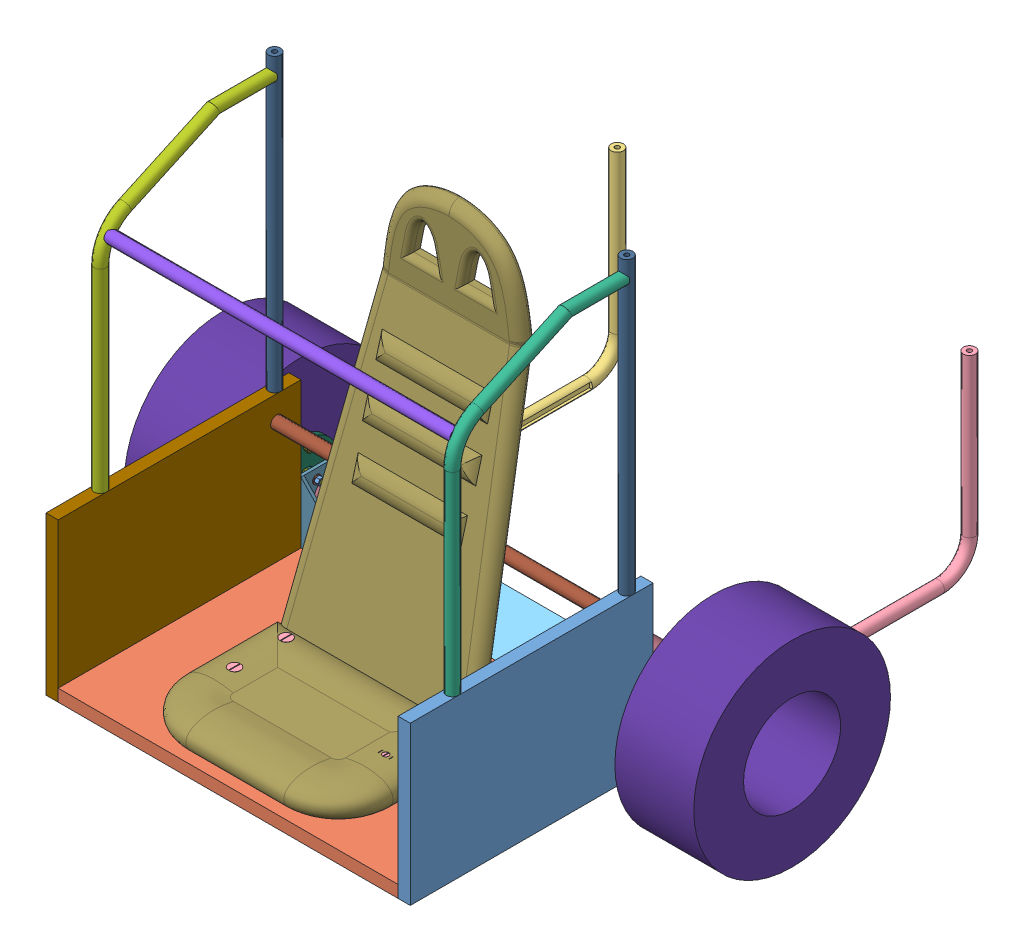
SolidWorks assembly MC (1), configuration Default. Lengths in mm.
Overall size (1191.26 1083.62 1291.85).
109 component instances, 22 part files, 141 mates.
Components (placement in the parent):
- SPL-1: SPL [Default] at (646.5449 178.7927 -996.551) size (25.4 330.2 508)
- BP-1: BP [Default] at (111.0665 -124.6065 -917.4807) size (711.2 25.4 508)
- BBR-2: BBR [Default] at (-77.3551 -47.0728 -1647.3326) x (-1 0 0) z (0 -1 0) size (25.4 687.13 407.73)
- BBL-1: BBL [Default] at (659.2449 -47.0728 -1647.3326) x (-1 0 0) z (0 -1 0) size (25.4 687.13 407.73)
- BC-1: BC [Default] at (357.2961 -116.9228 -1190.1326) x (-1 0 0) z (0 0 -1) size (723.9 12.7 152.4)
- FTL-1: FTL [Default] at (659.245 611.9935 -719.4116) x (0 -0.899323 -0.437285) z (-1 0 -0.000001) size (433.75 589.6 27.41)
- FTR-1: FTR [Default] at (-77.355 611.9935 -719.4116) x (0 -0.899323 -0.437285) z (-1 0 -0.000001) size (433.75 589.6 27.38)
- TC-1: TC [Default] at (652.8949 660.2535 -644.2461) x (0 -0.542655 -0.839955) z (-1 0 -0.000001) size (25.4 25.4 723.9)
- SPR-1: SPR [Default] at (-90.0551 178.7927 -996.551) size (25.4 330.2 508)
- BT-1: BT [Default] at (-77.3551 205.5935 -995.2506) x (0.000001 0 -1) z (1 0 0.000001) size (25.4 609.6 25.4)
- BT-2: BT [Default] at (659.2449 205.5935 -995.2506) x (0.000001 0 -1) z (1 0 0.000001) size (25.4 609.6 25.4)
- FB-1: FB [Default] at (-71.0051 154.7935 -986.9326) x (1 0 0) z (0 0.990518 0.137381) size (723.9 25.4 25.4)
- seat-1: seat [Default] at (291.4237 -99.2065 -836.1249) size (437.03 835.23 478.09)
- EA1-1: EA1 [Default] at (125.7912 -160.5315 -1174.1403) x (0 0 1) z (-1 0 0) size (411.48 411.48 1349.16)
  - EB1-1: EB1 [Default] at (60.2077 126.1588 196.7963) size (101.6 101.6 238.25)
  - EP1-1: EP1 [Default] at (60.2077 56.3088 69.7963) x (0 0 1) z (-1 0 0) size (254 133.35 152.4)
  - EA2-1: EA2 [Default] at (45.9187 58.6487 138.5565) size (411.48 411.48 213.36)
    - EP2-1: EP2 [Default] at (14.289 67.5101 114.1198) size (127 127 48.26)
    - hex bolt_ai-1: hex bolt_ai [HBOLT 0.4375-20x1.375x1.125-N] at (-36.511 67.5101 106.0934) x (0 0 1) z (-0.866025 -0.5 0) size (42.95 18.33 15.88)
    - hex bolt_ai-2: hex bolt_ai [HBOLT 0.4375-20x1.375x1.125-N] at (14.289 118.3101 106.0934) x (0 0 1) z (0 -1 0) size (42.95 18.33 15.88)
    - hex bolt_ai-3: hex bolt_ai [HBOLT 0.4375-20x1.375x1.125-N] at (14.289 16.7101 106.0934) x (0 0 1) z (-0.866025 0.5 0) size (42.95 18.33 15.88)
    - hex bolt_ai-4: hex bolt_ai [HBOLT 0.4375-20x1.375x1.125-N] at (65.089 67.5101 106.0934) x (0 0 1) z (-0.866025 0.5 0) size (42.95 18.33 15.88)
    - EB2-1: EB2 [Default] at (14.289 67.5101 129.9948) x (-1 0 0) z (0 0 -1) size (411.48 411.48 165.1)
    - flat washer type a wide_ai-1: flat washer type a wide_ai [Preferred Wide FW 0.4375] at (-36.511 67.5101 132.103) x (0 0 1) z (-0.923728 -0.383049 0) size (2.11 31.75 31.75)
    - flat washer type a wide_ai-2: flat washer type a wide_ai [Preferred Wide FW 0.4375] at (14.289 118.3101 132.103) x (0 0 1) z (1 0 0) size (2.11 31.75 31.75)
    - flat washer type a wide_ai-3: flat washer type a wide_ai [Preferred Wide FW 0.4375] at (14.289 16.7101 132.103) x (0 0 1) z (1 0 0) size (2.11 31.75 31.75)
    - flat washer type a wide_ai-4: flat washer type a wide_ai [Preferred Wide FW 0.4375] at (65.089 67.5101 132.103) x (0 0 1) z (1 0 0) size (2.11 31.75 31.75)
    - hex thick nut_ai-1: hex thick nut_ai [HTNUT 0.4375-14-D-N] at (14.289 16.7101 143.8632) x (0.055202 -0.998475 0) z (0 0 1) size (17.48 20.18 11.76)
    - hex thick nut_ai-2: hex thick nut_ai [HTNUT 0.4375-14-D-N] at (-36.511 67.5101 143.8632) x (0.547044 -0.837104 0) z (0 0 1) size (17.48 20.18 11.76)
    - hex thick nut_ai-3: hex thick nut_ai [HTNUT 0.4375-14-D-N] at (65.089 67.5101 143.8632) x (-0.982324 -0.18719 0) z (0 0 1) size (17.48 20.18 11.76)
    - hex thick nut_ai-4: hex thick nut_ai [HTNUT 0.4375-14-D-N] at (14.289 118.3101 143.8632) x (0.055202 -0.998475 0) z (0 0 1) size (17.48 20.18 11.76)
  - hex bolt_ai-8: hex bolt_ai [HBOLT 0.3125-18x1.375x0.875-N] at (17.0277 169.3388 215.4653) x (0 0 -1) z (0 1 0) size (40.89 14.66 12.7)
  - hex bolt_ai-9: hex bolt_ai [HBOLT 0.3125-18x1.375x0.875-N] at (103.3877 169.3388 215.4653) x (0 0 -1) z (0.866025 -0.5 0) size (40.89 14.66 12.7)
  - hex bolt_ai-10: hex bolt_ai [HBOLT 0.3125-18x1.375x0.875-N] at (103.3877 82.9788 215.4653) x (0 0 -1) z (0.866025 0.5 0) size (40.89 14.66 12.7)
  - hex bolt_ai-11: hex bolt_ai [HBOLT 0.3125-18x1.375x0.875-N] at (17.0277 82.9788 215.4653) x (0 0 -1) z (-0.866025 -0.5 0) size (40.89 14.66 12.7)
  - flat washer type a narrow_ai-1: flat washer type a narrow_ai [Preferred Narrow FW 0.3125] at (17.0277 169.3388 190.4463) x (0 0 1) z (-1 0 0) size (1.65 17.48 17.48)
  - flat washer type a narrow_ai-2: flat washer type a narrow_ai [Preferred Narrow FW 0.3125] at (103.3877 82.9788 190.4463) x (0 0 1) z (-1 0 0) size (1.65 17.48 17.48)
  - flat washer type a narrow_ai-3: flat washer type a narrow_ai [Preferred Narrow FW 0.3125] at (17.0277 82.9788 188.7953) x (0 0 -1) z (1 0 0) size (1.65 17.48 17.48)
  - flat washer type a narrow_ai-4: flat washer type a narrow_ai [Preferred Narrow FW 0.3125] at (103.3877 169.3388 188.7953) x (0 0 -1) z (0.923728 0.383049 0) size (1.65 17.48 17.48)
  - hex thick nut_ai-1: hex thick nut_ai [HTNUT 0.3125-18-D-N] at (103.3877 169.3388 188.7953) x (0.866025 0.5 0) z (0 0 1) size (12.7 14.66 8.53)
  - hex thick nut_ai-2: hex thick nut_ai [HTNUT 0.3125-18-D-N] at (17.0277 82.9788 180.2609) x (-0.866025 0.5 0) z (0 0 -1) size (12.7 14.66 8.53)
  - hex thick nut_ai-3: hex thick nut_ai [HTNUT 0.3125-18-D-N] at (103.3877 82.9788 181.9119) x (-0.866025 -0.5 0) z (0 0 -1) size (12.7 14.66 8.53)
  - hex thick nut_ai-4: hex thick nut_ai [HTNUT 0.3125-18-D-N] at (17.0277 169.3388 180.2609) x (-0.866025 -0.5 0) z (0 0 -1) size (12.7 14.66 8.53)
- EA1-2: EA1 [Default] at (456.0986 -160.5315 -1053.7249) x (0 0 -1) z (1 0 0) size (411.48 411.48 1349.16)
  - EB1-1: EB1 [Default] at (60.2077 126.1588 196.7963) size (101.6 101.6 238.25)
  - EP1-1: EP1 [Default] at (60.2077 56.3088 69.7963) x (0 0 1) z (-1 0 0) size (254 133.35 152.4)
  - EA2-1: EA2 [Default] at (45.9187 58.6487 138.5565) size (411.48 411.48 213.36)
    - EP2-1: EP2 [Default] at (14.289 67.5101 114.1198) size (127 127 48.26)
    - hex bolt_ai-1: hex bolt_ai [HBOLT 0.4375-20x1.375x1.125-N] at (-36.511 67.5101 106.0934) x (0 0 1) z (-0.866025 -0.5 0) size (42.95 18.33 15.88)
    - hex bolt_ai-2: hex bolt_ai [HBOLT 0.4375-20x1.375x1.125-N] at (14.289 118.3101 106.0934) x (0 0 1) z (0 -1 0) size (42.95 18.33 15.88)
    - hex bolt_ai-3: hex bolt_ai [HBOLT 0.4375-20x1.375x1.125-N] at (14.289 16.7101 106.0934) x (0 0 1) z (-0.866025 0.5 0) size (42.95 18.33 15.88)
    - hex bolt_ai-4: hex bolt_ai [HBOLT 0.4375-20x1.375x1.125-N] at (65.089 67.5101 106.0934) x (0 0 1) z (-0.866025 0.5 0) size (42.95 18.33 15.88)
    - EB2-1: EB2 [Default] at (14.289 67.5101 129.9948) x (-1 0 0) z (0 0 -1) size (411.48 411.48 165.1)
    - flat washer type a wide_ai-1: flat washer type a wide_ai [Preferred Wide FW 0.4375] at (-36.511 67.5101 132.103) x (0 0 1) z (-0.923728 -0.383049 0) size (2.11 31.75 31.75)
    - flat washer type a wide_ai-2: flat washer type a wide_ai [Preferred Wide FW 0.4375] at (14.289 118.3101 132.103) x (0 0 1) z (1 0 0) size (2.11 31.75 31.75)
    - flat washer type a wide_ai-3: flat washer type a wide_ai [Preferred Wide FW 0.4375] at (14.289 16.7101 132.103) x (0 0 1) z (1 0 0) size (2.11 31.75 31.75)
    - flat washer type a wide_ai-4: flat washer type a wide_ai [Preferred Wide FW 0.4375] at (65.089 67.5101 132.103) x (0 0 1) z (1 0 0) size (2.11 31.75 31.75)
    - hex thick nut_ai-1: hex thick nut_ai [HTNUT 0.4375-14-D-N] at (14.289 16.7101 143.8632) x (0.055202 -0.998475 0) z (0 0 1) size (17.48 20.18 11.76)
    - hex thick nut_ai-2: hex thick nut_ai [HTNUT 0.4375-14-D-N] at (-36.511 67.5101 143.8632) x (0.547044 -0.837104 0) z (0 0 1) size (17.48 20.18 11.76)
    - hex thick nut_ai-3: hex thick nut_ai [HTNUT 0.4375-14-D-N] at (65.089 67.5101 143.8632) x (-0.982324 -0.18719 0) z (0 0 1) size (17.48 20.18 11.76)
    - hex thick nut_ai-4: hex thick nut_ai [HTNUT 0.4375-14-D-N] at (14.289 118.3101 143.8632) x (0.055202 -0.998475 0) z (0 0 1) size (17.48 20.18 11.76)
  - hex bolt_ai-8: hex bolt_ai [HBOLT 0.3125-18x1.375x0.875-N] at (17.0277 169.3388 215.4653) x (0 0 -1) z (0 1 0) size (40.89 14.66 12.7)
  - hex bolt_ai-9: hex bolt_ai [HBOLT 0.3125-18x1.375x0.875-N] at (103.3877 169.3388 215.4653) x (0 0 -1) z (0.866025 -0.5 0) size (40.89 14.66 12.7)
  - hex bolt_ai-10: hex bolt_ai [HBOLT 0.3125-18x1.375x0.875-N] at (103.3877 82.9788 215.4653) x (0 0 -1) z (0.866025 0.5 0) size (40.89 14.66 12.7)
  - hex bolt_ai-11: hex bolt_ai [HBOLT 0.3125-18x1.375x0.875-N] at (17.0277 82.9788 215.4653) x (0 0 -1) z (-0.866025 -0.5 0) size (40.89 14.66 12.7)
  - flat washer type a narrow_ai-1: flat washer type a narrow_ai [Preferred Narrow FW 0.3125] at (17.0277 169.3388 190.4463) x (0 0 1) z (-1 0 0) size (1.65 17.48 17.48)
  - flat washer type a narrow_ai-2: flat washer type a narrow_ai [Preferred Narrow FW 0.3125] at (103.3877 82.9788 190.4463) x (0 0 1) z (-1 0 0) size (1.65 17.48 17.48)
  - flat washer type a narrow_ai-3: flat washer type a narrow_ai [Preferred Narrow FW 0.3125] at (17.0277 82.9788 188.7953) x (0 0 -1) z (1 0 0) size (1.65 17.48 17.48)
  - flat washer type a narrow_ai-4: flat washer type a narrow_ai [Preferred Narrow FW 0.3125] at (103.3877 169.3388 188.7953) x (0 0 -1) z (0.923728 0.383049 0) size (1.65 17.48 17.48)
  - hex thick nut_ai-1: hex thick nut_ai [HTNUT 0.3125-18-D-N] at (103.3877 169.3388 188.7953) x (0.866025 0.5 0) z (0 0 1) size (12.7 14.66 8.53)
  - hex thick nut_ai-2: hex thick nut_ai [HTNUT 0.3125-18-D-N] at (17.0277 82.9788 180.2609) x (-0.866025 0.5 0) z (0 0 -1) size (12.7 14.66 8.53)
  - hex thick nut_ai-3: hex thick nut_ai [HTNUT 0.3125-18-D-N] at (103.3877 82.9788 181.9119) x (-0.866025 -0.5 0) z (0 0 -1) size (12.7 14.66 8.53)
  - hex thick nut_ai-4: hex thick nut_ai [HTNUT 0.3125-18-D-N] at (17.0277 169.3388 180.2609) x (-0.866025 -0.5 0) z (0 0 -1) size (12.7 14.66 8.53)
- hex bolt_ai-1: hex bolt_ai [HBOLT 0.5000-13x1.375x1.25-N] at (157.5949 -88.6272 -1164.7326) x (0 -1 0) z (-1 0 0) size (44.17 22 19.05)
- hex bolt_ai-2: hex bolt_ai [HBOLT 0.5000-13x1.375x1.25-N] at (157.5949 -88.6272 -1063.1326) x (0 -1 0) z (0.5 0 -0.866025) size (44.17 22 19.05)
- hex bolt_ai-3: hex bolt_ai [HBOLT 0.5000-13x1.375x1.25-N] at (424.2949 -88.6272 -1063.1326) x (0 -1 0) z (1 0 0) size (44.17 22 19.05)
- hex bolt_ai-4: hex bolt_ai [HBOLT 0.5000-13x1.375x1.25-N] at (602.0949 -88.6272 -1164.7326) x (0 -1 0) z (-0.5 0 -0.866025) size (44.17 22 19.05)
- hex bolt_ai-5: hex bolt_ai [HBOLT 0.5000-13x1.375x1.25-N] at (424.2949 -88.6272 -1164.7326) x (0 -1 0) z (0.5 0 -0.866025) size (44.17 22 19.05)
- hex bolt_ai-6: hex bolt_ai [HBOLT 0.5000-13x1.375x1.25-N] at (602.0949 -88.6272 -1063.1326) x (0 -1 0) z (-0.5 0 0.866025) size (44.17 22 19.05)
- hex bolt_ai-7: hex bolt_ai [HBOLT 0.5000-13x1.375x1.25-N] at (-20.2051 -88.6272 -1164.7326) x (0 -1 0) z (-1 0 0) size (44.17 22 19.05)
- hex bolt_ai-8: hex bolt_ai [HBOLT 0.5000-13x1.375x1.25-N] at (-20.2051 -88.6272 -1063.1326) x (0 -1 0) z (1 0 0) size (44.17 22 19.05)
- flat washer type a wide_ai-1: flat washer type a wide_ai [Preferred Wide FW 0.5] at (157.5949 -119.6914 -1063.1326) x (0 -1 0) z (0.546944 0 -0.837169) size (2.77 34.92 34.92)
- flat washer type a wide_ai-2: flat washer type a wide_ai [Preferred Wide FW 0.5] at (157.5949 -119.6914 -1164.7326) x (0 -1 0) z (0.967366 0 0.253384) size (2.77 34.92 34.92)
- flat washer type a wide_ai-3: flat washer type a wide_ai [Preferred Wide FW 0.5] at (424.2949 -119.6914 -1164.7326) x (0 -1 0) z (-0.558017 0 -0.829829) size (2.77 34.92 34.92)
- flat washer type a wide_ai-4: flat washer type a wide_ai [Preferred Wide FW 0.5] at (-20.2051 -119.6914 -1063.1326) x (0 -1 0) z (0.590888 0 -0.806754) size (2.77 34.92 34.92)
- flat washer type a wide_ai-5: flat washer type a wide_ai [Preferred Wide FW 0.5] at (602.0949 -119.6914 -1063.1326) x (0 -1 0) z (0.610265 0 -0.792197) size (2.77 34.92 34.92)
- flat washer type a wide_ai-6: flat washer type a wide_ai [Preferred Wide FW 0.5] at (424.2949 -119.6914 -1063.1326) x (0 -1 0) z (0.837672 0 -0.546174) size (2.77 34.92 34.92)
- flat washer type a wide_ai-7: flat washer type a wide_ai [Preferred Wide FW 0.5] at (602.0949 -119.6914 -1164.7326) x (0 -1 0) z (0.97172 0 -0.236136) size (2.77 34.92 34.92)
- flat washer type a wide_ai-8: flat washer type a wide_ai [Preferred Wide FW 0.5] at (-20.2051 -119.6914 -1164.7326) x (0 -1 0) z (0.345214 0 -0.938524) size (2.77 34.92 34.92)
- hex nut_ai-1: hex nut_ai [HNUT 0.5000-13-D-N] at (157.5949 -131.0706 -1063.1326) x (-0.5 0 -0.866025) z (0 -1 0) size (19.05 22 11.38)
- hex nut_ai-2: hex nut_ai [HNUT 0.5000-13-D-N] at (-20.2051 -131.0706 -1164.7326) x (-0.866025 0 -0.5) z (0 -1 0) size (19.05 22 11.38)
- hex nut_ai-3: hex nut_ai [HNUT 0.5000-13-D-N] at (-20.2051 -131.0706 -1063.1326) x (0 0 -1) z (0 -1 0) size (19.05 22 11.38)
- hex nut_ai-4: hex nut_ai [HNUT 0.5000-13-D-N] at (157.5949 -131.0706 -1164.7326) x (0 0 -1) z (0 -1 0) size (19.05 22 11.38)
- hex nut_ai-5: hex nut_ai [HNUT 0.5000-13-D-N] at (424.2949 -131.0706 -1063.1326) x (0 0 1) z (0 -1 0) size (19.05 22 11.38)
- hex nut_ai-6: hex nut_ai [HNUT 0.5000-13-D-N] at (424.2949 -131.0706 -1164.7326) x (-0.866025 0 0.5) z (0 -1 0) size (19.05 22 11.38)
- hex nut_ai-8: hex nut_ai [HNUT 0.5000-13-D-N] at (602.0949 -131.0706 -1063.1326) x (-0.866025 0 -0.5) z (0 -1 0) size (19.05 22 11.38)
- hex nut_ai-9: hex nut_ai [HNUT 0.5000-13-D-N] at (602.0949 -131.0706 -1164.7326) x (-0.866025 0 -0.5) z (0 -1 0) size (19.05 22 11.38)
- flat washer type a wide_ai-9: flat washer type a wide_ai [Preferred Wide FW 0.5] at (132.9569 -124.6065 -809.1326) x (0 1 0) z (0 0 1) size (2.77 34.92 34.92)
- flat washer type a wide_ai-10: flat washer type a wide_ai [Preferred Wide FW 0.5] at (132.9569 -124.6065 -701.1826) x (0 1 0) z (0 0 1) size (2.77 34.92 34.92)
- flat washer type a wide_ai-11: flat washer type a wide_ai [Preferred Wide FW 0.5] at (449.1869 -124.6065 -701.1826) x (0 1 0) z (0 0 1) size (2.77 34.92 34.92)
- flat washer type a wide_ai-12: flat washer type a wide_ai [Preferred Wide FW 0.5] at (449.1869 -124.6065 -809.1326) x (0 1 0) z (0 0 1) size (2.77 34.92 34.92)
- hex nut_ai-10: hex nut_ai [HNUT 0.5000-13-D-N] at (132.9569 -138.7543 -809.1326) x (1 0 0) z (0 -1 0) size (19.05 22 11.38)
- hex nut_ai-11: hex nut_ai [HNUT 0.5000-13-D-N] at (132.9569 -138.7543 -701.1826) x (1 0 0) z (0 -1 0) size (19.05 22 11.38)
- hex nut_ai-12: hex nut_ai [HNUT 0.5000-13-D-N] at (449.1869 -138.7543 -809.1326) x (1 0 0) z (0 -1 0) size (19.05 22 11.38)
- hex nut_ai-13: hex nut_ai [HNUT 0.5000-13-D-N] at (449.1869 -138.7543 -701.1826) x (1 0 0) z (0 -1 0) size (19.05 22 11.38)
- countersunk bolt_ai2-1: countersunk bolt_ai2 [CSBOLT 0.2500-20x1x0.75-S-N] at (449.1869 -47.9829 -809.1326) x (0 -1 0) z (0 0 1) size (101.6 24.64 24.57)
- countersunk bolt_ai2-2: countersunk bolt_ai2 [CSBOLT 0.2500-20x1x0.75-S-N] at (449.1869 -48.4399 -701.1826) x (0 -1 0) z (0 0 1) size (101.6 24.64 24.57)
- countersunk bolt_ai2-3: countersunk bolt_ai2 [CSBOLT 0.2500-20x1x0.75-S-N] at (132.9569 -47.8327 -701.1826) x (0 -1 0) z (0 0 1) size (101.6 24.64 24.57)
- countersunk bolt_ai2-4: countersunk bolt_ai2 [CSBOLT 0.2500-20x1x0.75-S-N] at (132.9569 -47.9829 -809.1326) x (0 -1 0) z (0 0 1) size (101.6 24.64 24.57)
Mates (geometry in assembly coordinates):
- Coincident29: coincident: plane of SPL-1 through (671.9449 205.5935 -1037.7326) normal (0 0 -1); plane of BBL-1 through (659.2449 -111.9065 -1037.7326) normal (0 0 1)
- Tangent6: tangent: plane of SPL-1 through (671.9449 178.7927 -996.551) normal (1 0 0); cylinder of BBL-1 through (659.2449 -111.9065 -1037.7326) axis (0 0 -1) radius 12.7
- Tangent7: tangent: plane of SPL-1 through (671.9449 -124.6065 -529.7326) normal (0 -1 0); cylinder of BBL-1 through (659.2449 -111.9065 -1037.7326) axis (0 0 -1) radius 12.7
- Coincident32: coincident: plane of BP-1 through (-64.6551 -99.2065 -1037.7326) normal (0 0 -1); plane of BC-1 through (652.8949 -104.2228 -1037.7326) normal (0 0 1)
- Coincident34: coincident: plane of BBR-2 through (-71.0051 -104.2228 -1037.7326) normal (0 -1 0); plane of BC-1 through (357.2961 -104.2228 -1190.1326) normal (0 1 0)
- Tangent9: tangent: plane of SPL-1 through (671.9449 178.7927 -996.551) normal (1 0 0); cylinder of BBL-1 through (659.2449 283.1272 -1712.1664) axis (0 -1 0) radius 12.7
- Tangent10: tangent: plane of SPL-1 through (671.9449 178.7927 -996.551) normal (1 0 0); cylinder of FTL-1 through (659.2449 205.5935 -630.5357) axis (0 1 0) radius 12.7
- Coincident46: coincident: plane of SPL-1 through (646.5449 178.7927 -996.551) normal (-1 0 0); plane of BP-1 through (646.5449 -99.2065 -1037.7326) normal (1 0 0)
- Coincident48: coincident: plane of SPL-1 through (671.9449 -124.6065 -529.7326) normal (0 -1 0); plane of BP-1 through (111.0665 -124.6065 -917.4807) normal (0 -1 0)
- Parallel1: parallel: plane of BP-1 through (111.0665 -124.6065 -917.4807) normal (0 -1 0); plane of BC-1 through (357.2961 -116.9228 -1190.1326) normal (0 -1 0)
- Distance1: distance = 101.6 mm: cylinder of FTL-1 through (659.2449 205.5935 -630.5357) axis (0 1 0) radius 12.7; line of SPL-1 through (646.5449 205.5935 -529.7326) axis (0 -1 0)
- Coincident53: coincident: plane of FTR-1 through (-71.0051 660.2535 -644.2465) normal (1 0 0.000001); plane of TC-1 through (-71.0051 660.2535 -644.2465) normal (-1 0 -0.000001)
- Coincident55: coincident: plane of FTL-1 through (652.8949 660.2535 -644.2465) normal (-1 0 -0.000001); circle of TC-1
- Coincident56: coincident: plane of SPL-1 through (671.9449 205.5935 -1037.7326) normal (0 0 -1); plane of BP-1 through (-64.6551 -99.2065 -1037.7326) normal (0 0 -1)
- Coincident60: coincident: plane of SPL-1 through (671.9449 205.5935 -1037.7326) normal (0 0 -1); plane of BP-1 through (-64.6551 -99.2065 -1037.7326) normal (0 0 -1)
- Coincident61: coincident: plane of BP-1 through (111.0665 -124.6065 -917.4807) normal (0 -1 0); plane of SPR-1 through (-64.6551 -124.6065 -529.7326) normal (0 -1 0)
- Coincident62: coincident: plane of BP-1 through (-64.6551 -99.2065 -1037.7326) normal (-1 0 0); plane of SPR-1 through (-64.6551 178.7927 -996.551) normal (1 0 0)
- Coincident63: coincident: plane of BP-1 through (-64.6551 -99.2065 -1037.7326) normal (0 0 -1); plane of SPR-1 through (-64.6551 205.5935 -1037.7326) normal (0 0 -1)
- Tangent20: tangent: cylinder of BBR-2 through (-77.3551 -111.9065 -1037.7326) axis (0 0 -1) radius 12.7; plane of SPR-1 through (-90.0551 178.7927 -996.551) normal (-1 0 0)
- Tangent21: tangent: cylinder of BBR-2 through (-77.3551 -111.9065 -1037.7326) axis (0 0 -1) radius 12.7; plane of SPR-1 through (-64.6551 -124.6065 -529.7326) normal (0 -1 0)
- Tangent24: tangent: cylinder of BBR-2 through (-77.3551 -111.9065 -1037.7326) axis (0 0 -1) radius 12.7; plane of SPR-1 through (-64.6551 -124.6065 -529.7326) normal (0 -1 0)
- Coincident67: coincident: plane of BBR-2 through (-77.3551 -111.9065 -1037.7326) normal (0 0 1); plane of SPR-1 through (-64.6551 205.5935 -1037.7326) normal (0 0 -1)
- Parallel2: parallel: cylinder of BBR-2 through (-77.3551 283.1272 -1712.1664) axis (0 -1 0) radius 12.7; line of SPR-1 through (-64.6551 -124.6065 -1037.7326) axis (0 1 0)
- Coincident69: coincident: plane of SPR-1 through (-64.6551 205.5935 -529.7326) normal (0 1 0); plane of BT-1 through (-77.3551 205.5935 -995.2506) normal (0 -1 0)
- Coincident70: coincident: plane of SPL-1 through (671.9449 205.5935 -529.7326) normal (0 1 0); plane of BT-2 through (659.2449 205.5935 -995.2506) normal (0 -1 0)
- Coincident73: coincident: plane of SPR-1 through (-64.6551 205.5935 -529.7326) normal (0 1 0); plane of BT-1 through (-77.3551 205.5935 -995.2506) normal (0 -1 0)
- Tangent34: tangent: plane of SPR-1 through (-90.0551 178.7927 -996.551) normal (-1 0 0); cylinder of BT-1 through (-77.3551 815.1935 -995.2506) axis (0 -1 0) radius 12.7
- Tangent36: tangent: plane of SPL-1 through (671.9449 178.7927 -996.551) normal (1 0 0); cylinder of BT-2 through (659.2449 815.1935 -995.2506) axis (0 -1 0) radius 12.7
- Coincident74: coincident: plane of SPL-1 through (652.8949 154.7935 -986.9326) normal (-1 0 0); plane of FB-1 through (652.8949 154.7935 -986.9326) normal (1 0 0)
- Coincident75: coincident: plane of SPR-1 through (-71.0051 154.7935 -986.9326) normal (1 0 0); plane of FB-1 through (-71.0051 154.7935 -986.9326) normal (-1 0 0)
- Concentric1: concentric: circle of SPL-1; circle of FB-1
- Coincident77: coincident: plane of SPR-1 through (-71.0051 154.7935 -986.9326) normal (1 0 0); circle of FB-1
- Concentric2: concentric: circle of SPR-1; circle of FB-1
- Coincident81: coincident: plane of BP-1 through (111.0665 -99.2065 -917.4807) normal (0 1 0); plane of seat-1 through (507.3237 -99.2065 -820.9366) normal (0 -1 0)
- Coincident82: coincident: plane of FTR-1 through (-77.3551 205.5935 -630.5357) normal (0 -1 0); plane of SPR-1 through (-64.6551 205.5935 -529.7326) normal (0 1 0)
- Coincident83: coincident: plane of SPL-1 through (671.9449 205.5935 -529.7326) normal (0 1 0); plane of FTL-1 through (659.2449 205.5935 -630.5357) normal (0 -1 0)
- Coincident84: coincident: plane of BC-1 through (357.2961 -104.2228 -1190.1326) normal (0 1 0); plane of EA1-1/EP1-1 through (55.9949 -104.2228 -1113.9326) normal (0 -1 0)
- Concentric3: concentric: circle of BC-1; circle of EA1-1/EP1-1
- Concentric5: concentric: circle of BC-1; circle of EA1-1/EP1-1
- Coincident89: coincident: plane of BC-1 through (357.2961 -104.2228 -1190.1326) normal (0 1 0); plane of EA1-2/EP1-1 through (525.8949 -104.2228 -1113.9326) normal (0 -1 0)
- Concentric6: concentric: circle of BC-1; circle of EA1-2/EP1-1
- Concentric7: concentric: circle of BC-1; circle of EA1-2/EP1-1
- Concentric8: concentric: cylinder of EA1-1/EP1-1 through (157.5949 -123.2728 -1063.1326) axis (0 1 0) radius 6.35; cylinder of hex bolt_ai-2 through (157.5949 -88.6272 -1063.1326) axis (0 1 0) radius 6.35
- Coincident92: coincident: plane of EA1-1/EP1-1 through (55.9949 -97.8728 -1113.9326) normal (0 1 0); plane of hex bolt_ai-2 through (148.0699 -97.8728 -1046.6348) normal (0 -1 0)
- Parallel8: parallel: plane of EA1-1/EP1-1 through (182.9949 -97.8728 -1037.7326) normal (1 0 0); plane of hex bolt_ai-2 through (167.1199 -97.8728 -1057.6333) normal (1 0 0)
- Concentric9: concentric: cylinder of hex bolt_ai-2 through (157.5949 -88.6272 -1063.1326) axis (0 1 0) radius 6.35; cylinder of flat washer type a wide_ai-1 through (157.5949 -84.7664 -1063.1326) axis (0 1 0) radius 7.1374
- Coincident94: coincident: plane of BC-1 through (357.2961 -116.9228 -1190.1326) normal (0 -1 0); plane of flat washer type a wide_ai-1 through (142.9759 -116.9228 -1072.6836) normal (0 1 0)
- Concentric10: concentric: cylinder of hex bolt_ai-2 through (157.5949 -88.6272 -1063.1326) axis (0 1 0) radius 6.35; cylinder of hex nut_ai-1 through (157.5949 -119.6914 -1063.1326) axis (0 -1 0) radius 5.3581
- Coincident95: coincident: plane of flat washer type a wide_ai-1 through (151.6197 -119.6914 -1067.0364) normal (0 -1 0); plane of hex nut_ai-1 through (167.1199 -119.6914 -1046.6348) normal (0 1 0)
- Parallel9: parallel: plane of EA1-1/EP1-1 through (182.9949 -97.8728 -1037.7326) normal (1 0 0); plane of hex nut_ai-1 through (167.1199 -119.6914 -1068.6319) normal (1 0 0)
- Concentric11: concentric: cylinder of EA1-1/EP1-1 through (157.5949 -123.2728 -1164.7326) axis (0 1 0) radius 6.35; cylinder of hex bolt_ai-1 through (157.5949 -88.6272 -1164.7326) axis (0 1 0) radius 6.35
- Coincident97: coincident: plane of EA1-1/EP1-1 through (55.9949 -97.8728 -1113.9326) normal (0 1 0); plane of hex bolt_ai-1 through (176.6449 -97.8728 -1164.7326) normal (0 -1 0)
- Parallel10: parallel: plane of EA1-1/EP1-1 through (182.9949 -97.8728 -1037.7326) normal (1 0 0); plane of hex bolt_ai-1 through (167.1199 -97.8728 -1159.2333) normal (1 0 0)
- Concentric12: concentric: cylinder of EA1-2/EP1-1 through (424.2949 -123.2728 -1063.1326) axis (0 1 0) radius 6.35; cylinder of hex bolt_ai-3 through (424.2949 -88.6272 -1063.1326) axis (0 1 0) radius 6.35
- Coincident99: coincident: plane of EA1-2/EP1-1 through (525.8949 -97.8728 -1113.9326) normal (0 1 0); plane of hex bolt_ai-3 through (405.2449 -97.8728 -1063.1326) normal (0 -1 0)
- Parallel11: parallel: plane of EA1-2/EP1-1 through (398.8949 -97.8728 -1190.1326) normal (-1 0 0); plane of hex bolt_ai-3 through (433.8199 -97.8728 -1068.6319) normal (1 0 0)
- Concentric13: concentric: cylinder of BC-1 through (424.2949 -116.9228 -1164.7326) axis (0 1 0) radius 6.35; cylinder of hex bolt_ai-5 through (424.2949 -88.6272 -1164.7326) axis (0 1 0) radius 6.35
- Coincident101: coincident: plane of EA1-2/EP1-1 through (525.8949 -97.8728 -1113.9326) normal (0 1 0); plane of hex bolt_ai-5 through (414.7699 -97.8728 -1148.2348) normal (0 -1 0)
- Concentric14: concentric: cylinder of EA1-1/EP1-1 through (-20.2051 -123.2728 -1063.1326) axis (0 1 0) radius 6.35; cylinder of hex bolt_ai-8 through (-20.2051 -88.6272 -1063.1326) axis (0 1 0) radius 6.35
- Coincident102: coincident: plane of EA1-1/EP1-1 through (55.9949 -97.8728 -1113.9326) normal (0 1 0); plane of hex bolt_ai-8 through (-39.2551 -97.8728 -1063.1326) normal (0 -1 0)
- Parallel12: parallel: plane of EA1-1/EP1-1 through (182.9949 -97.8728 -1037.7326) normal (1 0 0); plane of hex bolt_ai-8 through (-10.6801 -97.8728 -1068.6319) normal (1 0 0)
- Concentric15: concentric: cylinder of EA1-1/EP1-1 through (-20.2051 -123.2728 -1164.7326) axis (0 1 0) radius 6.35; cylinder of hex bolt_ai-7 through (-20.2051 -88.6272 -1164.7326) axis (0 1 0) radius 6.35
- Coincident104: coincident: plane of EA1-1/EP1-1 through (55.9949 -97.8728 -1113.9326) normal (0 1 0); plane of hex bolt_ai-7 through (-1.1551 -97.8728 -1164.7326) normal (0 -1 0)
- Parallel13: parallel: plane of EA1-1/EP1-1 through (182.9949 -97.8728 -1037.7326) normal (1 0 0); plane of hex bolt_ai-7 through (-10.6801 -97.8728 -1159.2333) normal (1 0 0)
- Concentric16: concentric: cylinder of EA1-2/EP1-1 through (602.0949 -123.2728 -1164.7326) axis (0 1 0) radius 6.35; cylinder of hex bolt_ai-4 through (602.0949 -88.6272 -1164.7326) axis (0 1 0) radius 6.35
- Coincident106: coincident: plane of EA1-2/EP1-1 through (525.8949 -97.8728 -1113.9326) normal (0 1 0); plane of hex bolt_ai-4 through (611.6199 -97.8728 -1148.2348) normal (0 -1 0)
- Parallel14: parallel: plane of EA1-2/EP1-1 through (398.8949 -97.8728 -1190.1326) normal (-1 0 0); plane of hex bolt_ai-4 through (592.5699 -97.8728 -1159.2333) normal (-1 0 0)
- Concentric17: concentric: cylinder of EA1-2/EP1-1 through (602.0949 -123.2728 -1063.1326) axis (0 1 0) radius 6.35; cylinder of hex bolt_ai-6 through (602.0949 -88.6272 -1063.1326) axis (0 1 0) radius 6.35
- Coincident108: coincident: plane of EA1-2/EP1-1 through (525.8949 -97.8728 -1113.9326) normal (0 1 0); plane of hex bolt_ai-6 through (611.6199 -97.8728 -1079.6304) normal (0 -1 0)
- Parallel15: parallel: plane of EA1-2/EP1-1 through (398.8949 -97.8728 -1190.1326) normal (-1 0 0); plane of hex bolt_ai-6 through (592.5699 -97.8728 -1068.6319) normal (-1 0 0)
- Parallel16: parallel: plane of EA1-2/EP1-1 through (398.8949 -97.8728 -1190.1326) normal (-1 0 0); plane of hex bolt_ai-5 through (414.7699 -97.8728 -1159.2333) normal (-1 0 0)
- Concentric18: concentric: cylinder of hex bolt_ai-1 through (157.5949 -88.6272 -1164.7326) axis (0 1 0) radius 6.35; cylinder of flat washer type a wide_ai-2 through (157.5949 -84.7664 -1164.7326) axis (0 1 0) radius 7.1374
- Concentric19: concentric: cylinder of hex bolt_ai-8 through (-20.2051 -88.6272 -1063.1326) axis (0 1 0) radius 6.35; cylinder of flat washer type a wide_ai-4 through (-20.2051 -84.7664 -1063.1326) axis (0 1 0) radius 7.1374
- Concentric20: concentric: cylinder of hex bolt_ai-7 through (-20.2051 -88.6272 -1164.7326) axis (0 1 0) radius 6.35; cylinder of flat washer type a wide_ai-8 through (-20.2051 -84.7664 -1164.7326) axis (0 1 0) radius 7.1374
- Concentric21: concentric: cylinder of hex bolt_ai-5 through (424.2949 -88.6272 -1164.7326) axis (0 1 0) radius 6.35; cylinder of flat washer type a wide_ai-3 through (424.2949 -84.7664 -1164.7326) axis (0 1 0) radius 7.1374
- Concentric22: concentric: cylinder of hex bolt_ai-3 through (424.2949 -88.6272 -1063.1326) axis (0 1 0) radius 6.35; cylinder of flat washer type a wide_ai-6 through (424.2949 -84.7664 -1063.1326) axis (0 1 0) radius 7.1374
- Concentric23: concentric: cylinder of hex bolt_ai-6 through (602.0949 -88.6272 -1063.1326) axis (0 1 0) radius 6.35; cylinder of flat washer type a wide_ai-5 through (602.0949 -84.7664 -1063.1326) axis (0 1 0) radius 7.1374
- Concentric24: concentric: cylinder of hex bolt_ai-4 through (602.0949 -88.6272 -1164.7326) axis (0 1 0) radius 6.35; cylinder of flat washer type a wide_ai-7 through (602.0949 -84.7664 -1164.7326) axis (0 1 0) radius 7.1374
- Coincident111: coincident: plane of BC-1 through (357.2961 -116.9228 -1190.1326) normal (0 -1 0); plane of flat washer type a wide_ai-5 through (588.2612 -116.9228 -1073.7894) normal (0 1 0)
- Coincident112: coincident: plane of BC-1 through (357.2961 -116.9228 -1190.1326) normal (0 -1 0); plane of flat washer type a wide_ai-7 through (597.9714 -116.9228 -1181.7013) normal (0 1 0)
- Coincident113: coincident: plane of BC-1 through (357.2961 -116.9228 -1190.1326) normal (0 -1 0); plane of flat washer type a wide_ai-6 through (414.7574 -116.9228 -1077.7604) normal (0 1 0)
- Coincident114: coincident: plane of BC-1 through (357.2961 -116.9228 -1190.1326) normal (0 -1 0); plane of flat washer type a wide_ai-3 through (409.804 -116.9228 -1154.9882) normal (0 1 0)
- Coincident115: coincident: plane of BC-1 through (357.2961 -116.9228 -1190.1326) normal (0 -1 0); plane of flat washer type a wide_ai-2 through (162.0196 -116.9228 -1181.6252) normal (0 1 0)
- Coincident116: coincident: plane of BC-1 through (357.2961 -116.9228 -1190.1326) normal (0 -1 0); plane of flat washer type a wide_ai-4 through (-34.293 -116.9228 -1073.451) normal (0 1 0)
- Coincident117: coincident: plane of BC-1 through (357.2961 -116.9228 -1190.1326) normal (0 -1 0); plane of flat washer type a wide_ai-8 through (-36.5941 -116.9228 -1170.7609) normal (0 1 0)
- Concentric26: concentric: cylinder of hex bolt_ai-7 through (-20.2051 -88.6272 -1164.7326) axis (0 1 0) radius 6.35; cylinder of hex nut_ai-2 through (-20.2051 -119.6914 -1164.7326) axis (0 -1 0) radius 5.3581
- Concentric27: concentric: cylinder of hex bolt_ai-8 through (-20.2051 -88.6272 -1063.1326) axis (0 1 0) radius 6.35; cylinder of hex nut_ai-3 through (-20.2051 -119.6914 -1063.1326) axis (0 -1 0) radius 5.3581
- Concentric28: concentric: cylinder of hex bolt_ai-1 through (157.5949 -88.6272 -1164.7326) axis (0 1 0) radius 6.35; cylinder of hex nut_ai-4 through (157.5949 -119.6914 -1164.7326) axis (0 -1 0) radius 5.3581
- Concentric29: concentric: cylinder of hex bolt_ai-5 through (424.2949 -88.6272 -1164.7326) axis (0 1 0) radius 6.35; cylinder of hex nut_ai-6 through (424.2949 -119.6914 -1164.7326) axis (0 -1 0) radius 5.3581
- Concentric30: concentric: cylinder of hex bolt_ai-3 through (424.2949 -88.6272 -1063.1326) axis (0 1 0) radius 6.35; cylinder of hex nut_ai-5 through (424.2949 -119.6914 -1063.1326) axis (0 -1 0) radius 5.3581
- Concentric31: concentric: cylinder of hex bolt_ai-6 through (602.0949 -88.6272 -1063.1326) axis (0 1 0) radius 6.35; cylinder of hex nut_ai-8 through (602.0949 -119.6914 -1063.1326) axis (0 -1 0) radius 5.3581
- Concentric32: concentric: cylinder of hex bolt_ai-4 through (602.0949 -88.6272 -1164.7326) axis (0 1 0) radius 6.35; cylinder of hex nut_ai-9 through (602.0949 -119.6914 -1164.7326) axis (0 -1 0) radius 5.3581
- Coincident119: coincident: plane of flat washer type a wide_ai-2 through (159.4034 -119.6914 -1171.6371) normal (0 -1 0); plane of hex nut_ai-4 through (157.5949 -119.6914 -1145.6826) normal (0 1 0)
- Parallel18: parallel: plane of BC-1 through (652.8949 -104.2228 -1037.7326) normal (0 0 1); plane of hex nut_ai-4 through (163.0942 -119.6914 -1155.2076) normal (0 0 1)
- Coincident121: coincident: plane of flat washer type a wide_ai-8 through (-26.9037 -119.6914 -1167.1965) normal (0 -1 0); plane of hex nut_ai-2 through (-3.7073 -119.6914 -1155.2076) normal (0 1 0)
- Parallel19: parallel: plane of BC-1 through (652.8949 -104.2228 -1037.7326) normal (0 0 1); plane of hex nut_ai-2 through (-14.7058 -119.6914 -1155.2076) normal (0 0 1)
- Coincident123: coincident: plane of flat washer type a wide_ai-4 through (-25.9632 -119.6914 -1067.35) normal (0 -1 0); plane of hex nut_ai-3 through (-20.2051 -119.6914 -1044.0826) normal (0 1 0)
- Parallel20: parallel: plane of BC-1 through (652.8949 -104.2228 -1037.7326) normal (0 0 1); plane of hex nut_ai-3 through (-14.7058 -119.6914 -1053.6076) normal (0 0 1)
- Coincident125: coincident: plane of flat washer type a wide_ai-6 through (420.3967 -119.6914 -1069.1114) normal (0 -1 0); plane of hex nut_ai-5 through (424.2949 -119.6914 -1082.1826) normal (0 1 0)
- Parallel21: parallel: plane of BC-1 through (652.8949 -104.2228 -1037.7326) normal (0 0 1); plane of hex nut_ai-5 through (418.7957 -119.6914 -1053.6076) normal (0 0 1)
- Coincident127: coincident: plane of flat washer type a wide_ai-3 through (418.3721 -119.6914 -1160.7498) normal (0 -1 0); plane of hex nut_ai-6 through (440.7927 -119.6914 -1174.2576) normal (0 1 0)
- Parallel22: parallel: plane of BC-1 through (652.8949 -104.2228 -1037.7326) normal (0 0 1); plane of hex nut_ai-6 through (429.7942 -119.6914 -1155.2076) normal (0 0 1)
- Coincident129: coincident: plane of flat washer type a wide_ai-5 through (596.4407 -119.6914 -1067.4883) normal (0 -1 0); plane of hex nut_ai-8 through (618.5927 -119.6914 -1053.6076) normal (0 1 0)
- Parallel23: parallel: plane of BC-1 through (652.8949 -104.2228 -1037.7326) normal (0 0 1); plane of hex nut_ai-8 through (607.5942 -119.6914 -1053.6076) normal (0 0 1)
- Coincident131: coincident: plane of flat washer type a wide_ai-7 through (600.4095 -119.6914 -1171.6682) normal (0 -1 0); plane of hex nut_ai-9 through (618.5927 -119.6914 -1155.2076) normal (0 1 0)
- Parallel24: parallel: plane of BC-1 through (652.8949 -104.2228 -1037.7326) normal (0 0 1); plane of hex nut_ai-9 through (607.5942 -119.6914 -1155.2076) normal (0 0 1)
- Coincident133: coincident: plane of BBL-1 through (652.8949 -47.0728 -1647.3326) normal (-1 0 0); plane of BC-1 through (652.8949 -104.2228 -1037.7326) normal (1 0 0)
- Coincident135: coincident: plane of FTR-1 through (-64.6549 788.925 -988.9006) normal (0.000001 0 -1); plane of BT-1 through (-77.3551 777.3475 -988.9006) normal (-0.000001 0 1)
- Distance2: distance = 101.6 mm: line of SPR-1 through (-90.0551 205.5935 -529.7326) axis (0 -1 0); cylinder of FTR-1 through (-77.3551 205.5935 -630.5357) axis (0 1 0) radius 12.7
- Tangent39: tangent: curve of FTL-1; circle of BT-2
- Concentric43: concentric: cylinder of BP-1 through (132.9569 -124.6065 -809.1326) axis (0 1 0) radius 6.35; cylinder of flat washer type a wide_ai-9 through (132.9569 -159.5315 -809.1326) axis (0 -1 0) radius 7.1374
- Coincident136: coincident: plane of BP-1 through (111.0665 -124.6065 -917.4807) normal (0 -1 0); plane of flat washer type a wide_ai-9 through (125.8195 -124.6065 -809.1326) normal (0 1 0)
- Concentric44: concentric: cylinder of BP-1 through (132.9569 -124.6065 -701.1826) axis (0 1 0) radius 6.35; cylinder of flat washer type a wide_ai-10 through (132.9569 -159.5315 -701.1826) axis (0 -1 0) radius 7.1374
- Coincident137: coincident: plane of BP-1 through (111.0665 -124.6065 -917.4807) normal (0 -1 0); plane of flat washer type a wide_ai-10 through (125.8195 -124.6065 -701.1826) normal (0 1 0)
- Concentric45: concentric: cylinder of BP-1 through (449.1869 -124.6065 -701.1826) axis (0 1 0) radius 6.35; cylinder of flat washer type a wide_ai-11 through (449.1869 -159.5315 -701.1826) axis (0 -1 0) radius 7.1374
- Coincident138: coincident: plane of BP-1 through (111.0665 -124.6065 -917.4807) normal (0 -1 0); plane of flat washer type a wide_ai-11 through (442.0495 -124.6065 -701.1826) normal (0 1 0)
- Concentric46: concentric: cylinder of BP-1 through (449.1869 -124.6065 -809.1326) axis (0 1 0) radius 6.35; cylinder of flat washer type a wide_ai-12 through (449.1869 -159.5315 -809.1326) axis (0 -1 0) radius 7.1374
- Coincident139: coincident: plane of BP-1 through (111.0665 -124.6065 -917.4807) normal (0 -1 0); plane of flat washer type a wide_ai-12 through (442.0495 -124.6065 -809.1326) normal (0 1 0)
- Concentric47: concentric: cylinder of flat washer type a wide_ai-9 through (132.9569 -159.5315 -809.1326) axis (0 -1 0) radius 17.4625; cylinder of hex nut_ai-10 through (132.9569 -113.7168 -809.1326) axis (0 -1 0) radius 6.35
- Coincident140: coincident: plane of flat washer type a wide_ai-9 through (115.4944 -127.3751 -809.1326) normal (0 -1 0); plane of hex nut_ai-10 through (113.9069 -127.3751 -809.1326) normal (0 1 0)
- Concentric48: concentric: cylinder of flat washer type a wide_ai-10 through (132.9569 -159.5315 -701.1826) axis (0 -1 0) radius 17.4625; cylinder of hex nut_ai-11 through (132.9569 -113.7168 -701.1826) axis (0 -1 0) radius 6.35
- Coincident141: coincident: plane of flat washer type a wide_ai-10 through (115.4944 -127.3751 -701.1826) normal (0 -1 0); plane of hex nut_ai-11 through (113.9069 -127.3751 -701.1826) normal (0 1 0)
- Concentric49: concentric: cylinder of flat washer type a wide_ai-12 through (449.1869 -159.5315 -809.1326) axis (0 -1 0) radius 17.4625; cylinder of hex nut_ai-12 through (449.1869 -113.7168 -809.1326) axis (0 -1 0) radius 6.35
- Coincident142: coincident: plane of flat washer type a wide_ai-12 through (431.7244 -127.3751 -809.1326) normal (0 -1 0); plane of hex nut_ai-12 through (430.1369 -127.3751 -809.1326) normal (0 1 0)
- Concentric50: concentric: cylinder of flat washer type a wide_ai-11 through (449.1869 -159.5315 -701.1826) axis (0 -1 0) radius 17.4625; cylinder of hex nut_ai-13 through (449.1869 -113.7168 -701.1826) axis (0 -1 0) radius 6.35
- Coincident143: coincident: plane of flat washer type a wide_ai-11 through (431.7244 -127.3751 -701.1826) normal (0 -1 0); plane of hex nut_ai-13 through (430.1369 -127.3751 -701.1826) normal (0 1 0)
- Tangent50: tangent: plane of FTR-1 through (-71.0051 660.2535 -644.2465) normal (1 0 0.000001); circle of TC-1
- Concentric60: concentric: cylinder of FTR-1 through (-71.0051 660.2535 -644.2465) axis (1 0 0.000001) radius 12.7; cylinder of TC-1 through (-71.0051 660.2535 -644.2465) axis (1 0 0.000001) radius 12.7
- Concentric63: concentric: cylinder of BP-1 through (132.9569 -124.6065 -809.1326) axis (0 1 0) radius 6.35; cylinder of seat-1 through (132.9569 260.8303 -809.1326) axis (0 -1 0) radius 6.35
- Tangent51: tangent: face of FTL-1; cylinder of BT-2 through (659.2449 777.3475 -988.9006) axis (-0.000001 0 1) radius 12.7
- Parallel25: parallel: plane of BC-1 through (357.2961 -116.9228 -1190.1326) normal (0 -1 0); plane of flat washer type a wide_ai-8 through (-26.9037 -119.6914 -1167.1965) normal (0 -1 0)
- Parallel26: parallel: cylinder of FTL-1 through (652.8949 660.2535 -644.2465) axis (-1 0 -0.000001) radius 12.7; cylinder of TC-1 through (-71.0051 660.2535 -644.2465) axis (1 0 0.000001) radius 12.7
- Tangent58: tangent: face of FTL-1; cylinder of BT-2 through (659.2449 777.3475 -988.9006) axis (-0.000001 0 1) radius 12.7
- Concentric68: concentric: cylinder of seat-1 through (449.1869 260.8303 -809.1326) axis (0 -1 0) radius 6.35; cylinder of countersunk bolt_ai2-1 through (449.1869 -41.6329 -809.1326) axis (0 1 0) radius 6.35
- Tangent64: tangent: face of seat-1; circle of countersunk bolt_ai2-1
- Concentric69: concentric: cylinder of seat-1 through (449.1869 260.8303 -701.1826) axis (0 -1 0) radius 6.35; cylinder of countersunk bolt_ai2-2 through (449.1869 -42.0899 -701.1826) axis (0 1 0) radius 6.35
- Tangent65: tangent: face of seat-1; circle of countersunk bolt_ai2-2
- Concentric70: concentric: cylinder of seat-1 through (132.9569 260.8303 -701.1826) axis (0 -1 0) radius 6.35; cylinder of countersunk bolt_ai2-3 through (132.9569 27.2686 -701.1826) axis (0 1 0) radius 6.35
- Concentric71: concentric: cylinder of seat-1 through (132.9569 260.8303 -809.1326) axis (0 -1 0) radius 6.35; cylinder of countersunk bolt_ai2-4 through (132.9569 -15.3703 -809.1326) axis (0 1 0) radius 6.35
- Tangent66: tangent: face of seat-1; circle of countersunk bolt_ai2-3
- Tangent67: tangent: face of seat-1; circle of countersunk bolt_ai2-4
